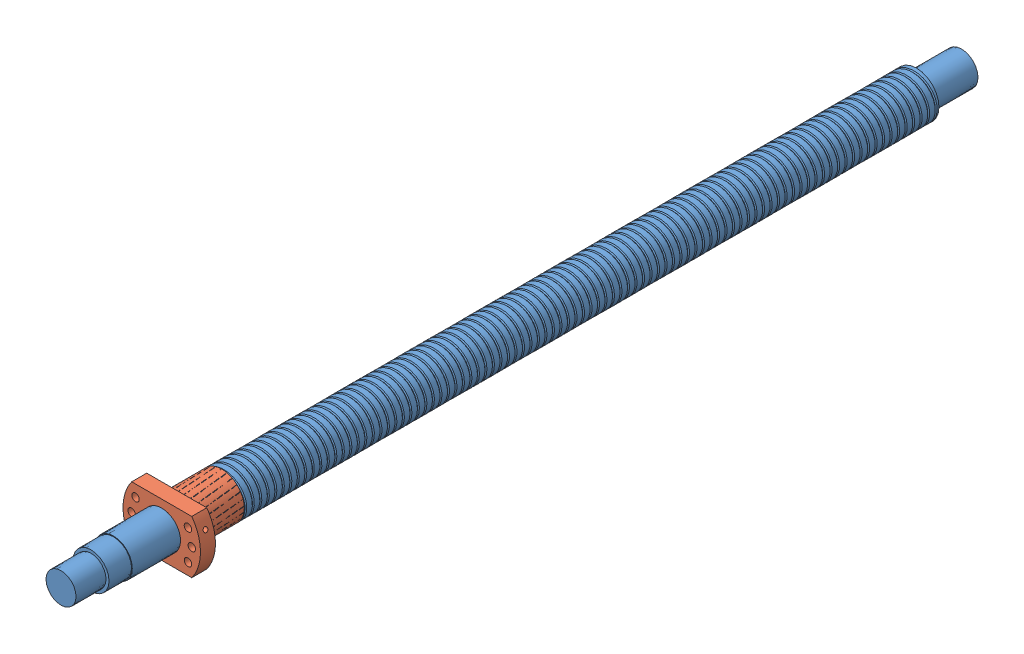
SolidWorks assembly Assem1, configuration Default. Lengths in mm.
Overall size (51.55 35.39 600).
2 component instances, 2 part files, 1 mates.
Components (placement in the parent):
- Ball Screew-1: Ball Screew [Default] at (165.3035 322.8076 465.243) size (30.56 30.52 600)
- Nut-1: Nut [Default] at (165.3035 322.8076 718.1319) size (51.55 35.39 40)
Mates (geometry in assembly coordinates):
- Concentric1: concentric anti-aligned: cylinder of Ball Screew-1 through (165.3035 322.8076 750.243) axis (0 0 -1) radius 12.5; cylinder of Nut-1 through (165.3035 322.8076 678.1319) axis (0 0 1) radius 12.5
